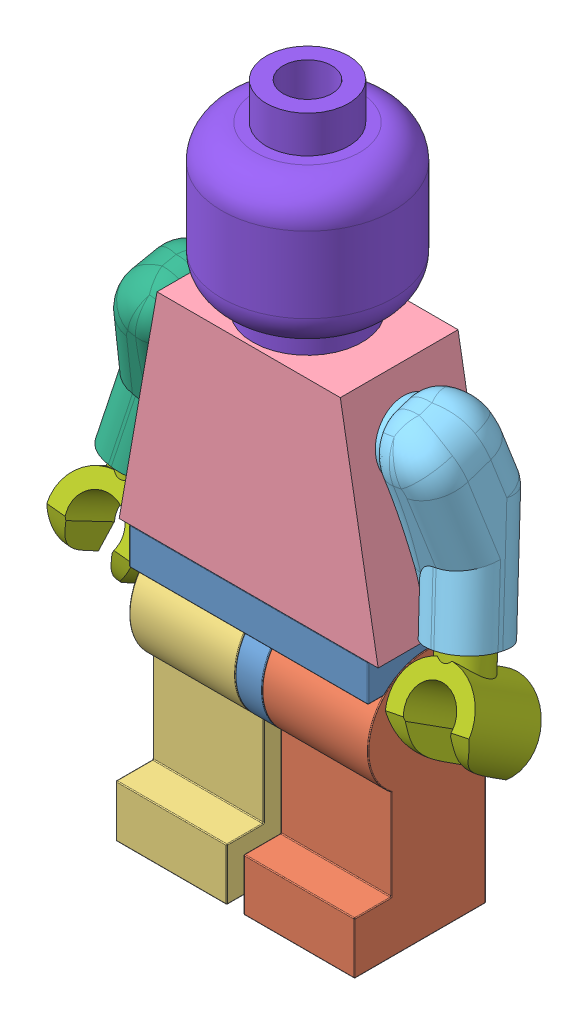
SolidWorks assembly Man, configuration Default. Lengths in mm.
Overall size (26.17 40.6 11.38).
11 component instances, 8 part files, 5 mates.
Components (placement in the parent):
- 9341-1: 9341 [Default] at (-2.9473 3.9615 -1.1361) size (14.2 20.5 7.98)
  - Base Leg Mid-1: Base Leg Mid [Default] at (-3.5924 -2.1836 1.4429) size (14.2 12.7 7)
  - Base Leg Left-1: Base Leg Left [Default] at (-3.0924 -13.4836 -2.0571) x (1 0 0) z (0 -1 0) size (6.6 7.98 14.8)
  - Base Leg Right-1: Base Leg Right [Default] at (-4.0924 -13.4836 -2.0571) x (1 0 0) z (0 -1 0) size (6.6 7.98 14.8)
- 4288003-1: 4288003 [Default] at (-2.9474 3.9615 -1.1361) size (26.17 24.55 11.38)
  - Base Torso-1: Base Torso [Default] at (-3.5924 8.8164 -2.0571) size (15.4 18.3 7)
  - Base Arm Left-1: Base Arm Left [Default] at (3.1062 8.1133 1.3031) x (0.166786 -0.948824 -0.268169) z (0.9849 0.173127 0) size (12.12 7.19 6.37)
  - Base Arm Right-1: Base Arm Right [Default] at (-18.1705 9.4967 1.3565) x (-0.167443 -0.952565 -0.254131) z (0.9849 -0.173127 0) size (12.12 7.19 6.37)
  - Base Hand-1: Base Hand [Default] at (6.6274 -1.4852 0.45) x (0.164395 -0.834148 0.526471) z (-0.985421 -0.162598 0.050083) size (10.77 6.15 4.9)
  - Base Hand-2: Base Hand [Default] at (-14.0754 -1.4513 0.6535) x (-0.119041 -0.834396 0.538156) z (-0.978765 0.189713 0.07764) size (10.77 6.15 4.9)
- 4168995-1: 4168995 [Default] at (-6.5398 20.3779 0.3068) size (10.2 11.9 10.2)
Mates (geometry in assembly coordinates):
- Concentric1: concentric aligned: cylinder of 4288003-1/Base Torso-1; cylinder of 4168995-1
- Coincident1: coincident anti-aligned: plane of 4288003-1/Base Torso-1 through (-1.0898 19.1779 3.8068) normal (0 1 0); plane of 4168995-1 through (-6.5398 19.1779 0.3068) normal (0 -1 0)
- Coincident4: coincident anti-aligned: plane of 9341-1/Base Leg Mid-1 through (-13.6397 6.3779 3.8068) normal (0 1 0); plane of 4288003-1/Base Torso-1 through (-14.2398 6.3779 3.8068) normal (0 -1 0)
- Coincident5: coincident aligned: plane of 9341-1/Base Leg Mid-1 through (-13.6397 6.3779 3.8068) normal (0 0 1); plane of 4288003-1/Base Torso-1 through (-1.0898 19.1779 3.8068) normal (0 0 1)
- Distance1: distance = 0.6021 mm: line of 4288003-1/Base Torso-1; line of 9341-1/Base Leg Mid-1
